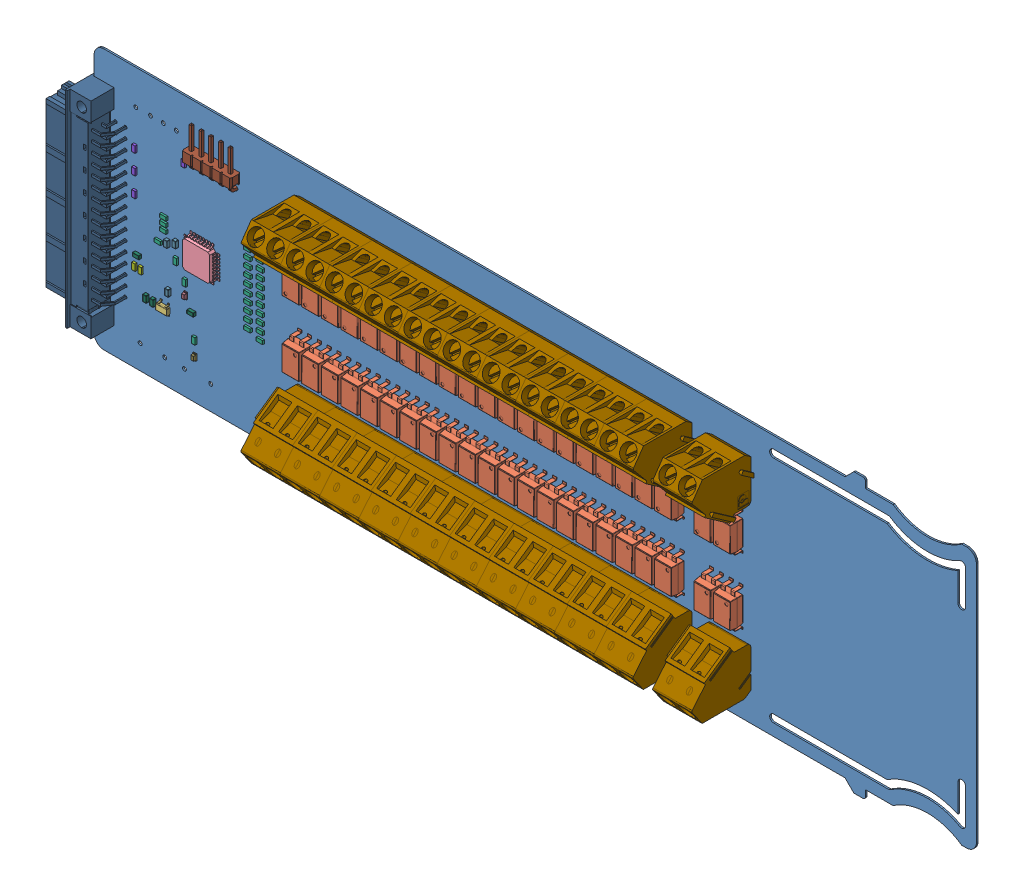
SolidWorks assembly DMM6500_Scan_card, configuration По умолчанию. Lengths in mm.
Overall size (235.68 72.14 18.8).
157 component instances, 15 part files, 0 mates.
Components (placement in the parent):
- DMM6500_Scan_card_BOARD-1: DMM6500_Scan_card_BOARD [По умолчанию] at origin size (228.6 72.14 0.41)
- SOP254P1000X380-4N_VOR1142B4-2-81: SOP254P1000X380-4N_VOR1142B4-2 [По умолчанию] at (125.83 50.8 0.4013) x (0 -1 0) z (0 0 1) size (10.02 4.7 3.8)
- SOP254P1000X380-4N_VOR1142B4-2-77: SOP254P1000X380-4N_VOR1142B4-2 [По умолчанию] at (120.75 50.8 0.4013) x (0 -1 0) z (0 0 1) size (10.02 4.7 3.8)
- SOP254P1000X380-4N_VOR1142B4-2-74: SOP254P1000X380-4N_VOR1142B4-2 [По умолчанию] at (115.67 50.8 0.4013) x (0 -1 0) z (0 0 1) size (10.02 4.7 3.8)
- SOP254P1000X380-4N_VOR1142B4-2-65: SOP254P1000X380-4N_VOR1142B4-2 [По умолчанию] at (110.59 50.8 0.4013) x (0 -1 0) z (0 0 1) size (10.02 4.7 3.8)
- SOP254P1000X380-4N_VOR1142B4-2-63: SOP254P1000X380-4N_VOR1142B4-2 [По умолчанию] at (105.51 50.8 0.4013) x (0 -1 0) z (0 0 1) size (10.02 4.7 3.8)
- SOP254P1000X380-4N_VOR1142B4-2-72: SOP254P1000X380-4N_VOR1142B4-2 [По умолчанию] at (100.43 50.8 0.4013) x (0 -1 0) z (0 0 1) size (10.02 4.7 3.8)
- SOP254P1000X380-4N_VOR1142B4-2-79: SOP254P1000X380-4N_VOR1142B4-2 [По умолчанию] at (95.35 50.8 0.4013) x (0 -1 0) z (0 0 1) size (10.02 4.7 3.8)
- SOP254P1000X380-4N_VOR1142B4-2-68: SOP254P1000X380-4N_VOR1142B4-2 [По умолчанию] at (90.27 50.8 0.4013) x (0 -1 0) z (0 0 1) size (10.02 4.7 3.8)
- SOP254P1000X380-4N_VOR1142B4-2-75: SOP254P1000X380-4N_VOR1142B4-2 [По умолчанию] at (85.19 50.8 0.4013) x (0 -1 0) z (0 0 1) size (10.02 4.7 3.8)
- SOP254P1000X380-4N_VOR1142B4-2-71: SOP254P1000X380-4N_VOR1142B4-2 [По умолчанию] at (80.11 50.8 0.4013) x (0 -1 0) z (0 0 1) size (10.02 4.7 3.8)
- SOP254P1000X380-4N_VOR1142B4-2-73: SOP254P1000X380-4N_VOR1142B4-2 [По умолчанию] at (176.63 50.8 0.4013) x (0 -1 0) z (0 0 1) size (10.02 4.7 3.8)
- SOP254P1000X380-4N_VOR1142B4-2-78: SOP254P1000X380-4N_VOR1142B4-2 [По умолчанию] at (171.55 50.8 0.4013) x (0 -1 0) z (0 0 1) size (10.02 4.7 3.8)
- SOP254P1000X380-4N_VOR1142B4-2-80: SOP254P1000X380-4N_VOR1142B4-2 [По умолчанию] at (166.47 50.8 0.4013) x (0 -1 0) z (0 0 1) size (10.02 4.7 3.8)
- SOP254P1000X380-4N_VOR1142B4-2-76: SOP254P1000X380-4N_VOR1142B4-2 [По умолчанию] at (161.39 50.8 0.4013) x (0 -1 0) z (0 0 1) size (10.02 4.7 3.8)
- SOP254P1000X380-4N_VOR1142B4-2-64: SOP254P1000X380-4N_VOR1142B4-2 [По умолчанию] at (156.31 50.8 0.4013) x (0 -1 0) z (0 0 1) size (10.02 4.7 3.8)
- SOP254P1000X380-4N_VOR1142B4-2-66: SOP254P1000X380-4N_VOR1142B4-2 [По умолчанию] at (151.23 50.8 0.4013) x (0 -1 0) z (0 0 1) size (10.02 4.7 3.8)
- SOP254P1000X380-4N_VOR1142B4-2-67: SOP254P1000X380-4N_VOR1142B4-2 [По умолчанию] at (146.15 50.8 0.4013) x (0 -1 0) z (0 0 1) size (10.02 4.7 3.8)
- SOP254P1000X380-4N_VOR1142B4-2-69: SOP254P1000X380-4N_VOR1142B4-2 [По умолчанию] at (141.07 50.8 0.4013) x (0 -1 0) z (0 0 1) size (10.02 4.7 3.8)
- SOP254P1000X380-4N_VOR1142B4-2-70: SOP254P1000X380-4N_VOR1142B4-2 [По умолчанию] at (135.99 50.8 0.4013) x (0 -1 0) z (0 0 1) size (10.02 4.7 3.8)
- SOP254P1000X380-4N_VOR1142B4-2-42: SOP254P1000X380-4N_VOR1142B4-2 [По умолчанию] at (130.91 50.8 0.4013) x (0 -1 0) z (0 0 1) size (10.02 4.7 3.8)
- SOP254P1000X380-4N_VOR1142B4-2-43: SOP254P1000X380-4N_VOR1142B4-2 [По умолчанию] at (191.87 50.8 0.4013) x (0 -1 0) z (0 0 1) size (10.02 4.7 3.8)
- SOP254P1000X380-4N_VOR1142B4-2-47: SOP254P1000X380-4N_VOR1142B4-2 [По умолчанию] at (186.79 50.8 0.4013) x (0 -1 0) z (0 0 1) size (10.02 4.7 3.8)
- SOP254P1000X380-4N_VOR1142B4-2-50: SOP254P1000X380-4N_VOR1142B4-2 [По умолчанию] at (125.83 67.91 0.4013) x (0 1 0) z (0 0 1) size (10.02 4.7 3.8)
- SOP254P1000X380-4N_VOR1142B4-2-48: SOP254P1000X380-4N_VOR1142B4-2 [По умолчанию] at (120.75 67.91 0.4013) x (0 1 0) z (0 0 1) size (10.02 4.7 3.8)
- SOP254P1000X380-4N_VOR1142B4-2-56: SOP254P1000X380-4N_VOR1142B4-2 [По умолчанию] at (115.67 67.91 0.4013) x (0 1 0) z (0 0 1) size (10.02 4.7 3.8)
- SOP254P1000X380-4N_VOR1142B4-2-44: SOP254P1000X380-4N_VOR1142B4-2 [По умолчанию] at (110.59 67.91 0.4013) x (0 1 0) z (0 0 1) size (10.02 4.7 3.8)
- SOP254P1000X380-4N_VOR1142B4-2-27: SOP254P1000X380-4N_VOR1142B4-2 [По умолчанию] at (105.51 67.91 0.4013) x (0 1 0) z (0 0 1) size (10.02 4.7 3.8)
- SOP254P1000X380-4N_VOR1142B4-2-58: SOP254P1000X380-4N_VOR1142B4-2 [По умолчанию] at (100.43 67.91 0.4013) x (0 1 0) z (0 0 1) size (10.02 4.7 3.8)
- SOP254P1000X380-4N_VOR1142B4-2-52: SOP254P1000X380-4N_VOR1142B4-2 [По умолчанию] at (95.35 67.91 0.4013) x (0 1 0) z (0 0 1) size (10.02 4.7 3.8)
- SOP254P1000X380-4N_VOR1142B4-2-59: SOP254P1000X380-4N_VOR1142B4-2 [По умолчанию] at (90.27 67.91 0.4013) x (0 1 0) z (0 0 1) size (10.02 4.7 3.8)
- SOP254P1000X380-4N_VOR1142B4-2-45: SOP254P1000X380-4N_VOR1142B4-2 [По умолчанию] at (85.19 67.91 0.4013) x (0 1 0) z (0 0 1) size (10.02 4.7 3.8)
- SOP254P1000X380-4N_VOR1142B4-2-46: SOP254P1000X380-4N_VOR1142B4-2 [По умолчанию] at (80.11 67.91 0.4013) x (0 1 0) z (0 0 1) size (10.02 4.7 3.8)
- SOP254P1000X380-4N_VOR1142B4-2-33: SOP254P1000X380-4N_VOR1142B4-2 [По умолчанию] at (176.63 67.91 0.4013) x (0 1 0) z (0 0 1) size (10.02 4.7 3.8)
- SOP254P1000X380-4N_VOR1142B4-2-60: SOP254P1000X380-4N_VOR1142B4-2 [По умолчанию] at (171.55 67.91 0.4013) x (0 1 0) z (0 0 1) size (10.02 4.7 3.8)
- SOP254P1000X380-4N_VOR1142B4-2-55: SOP254P1000X380-4N_VOR1142B4-2 [По умолчанию] at (166.47 67.91 0.4013) x (0 1 0) z (0 0 1) size (10.02 4.7 3.8)
- SOP254P1000X380-4N_VOR1142B4-2-57: SOP254P1000X380-4N_VOR1142B4-2 [По умолчанию] at (161.39 67.91 0.4013) x (0 1 0) z (0 0 1) size (10.02 4.7 3.8)
- SOP254P1000X380-4N_VOR1142B4-2-53: SOP254P1000X380-4N_VOR1142B4-2 [По умолчанию] at (156.31 67.91 0.4013) x (0 1 0) z (0 0 1) size (10.02 4.7 3.8)
- SOP254P1000X380-4N_VOR1142B4-2-41: SOP254P1000X380-4N_VOR1142B4-2 [По умолчанию] at (151.23 67.91 0.4013) x (0 1 0) z (0 0 1) size (10.02 4.7 3.8)
- SOP254P1000X380-4N_VOR1142B4-2-54: SOP254P1000X380-4N_VOR1142B4-2 [По умолчанию] at (146.15 67.91 0.4013) x (0 1 0) z (0 0 1) size (10.02 4.7 3.8)
- SOP254P1000X380-4N_VOR1142B4-2-40: SOP254P1000X380-4N_VOR1142B4-2 [По умолчанию] at (141.07 67.91 0.4013) x (0 1 0) z (0 0 1) size (10.02 4.7 3.8)
- SOP254P1000X380-4N_VOR1142B4-2-49: SOP254P1000X380-4N_VOR1142B4-2 [По умолчанию] at (135.99 67.91 0.4013) x (0 1 0) z (0 0 1) size (10.02 4.7 3.8)
- SOP254P1000X380-4N_VOR1142B4-2-61: SOP254P1000X380-4N_VOR1142B4-2 [По умолчанию] at (130.91 67.91 0.4013) x (0 1 0) z (0 0 1) size (10.02 4.7 3.8)
- SOP254P1000X380-4N_VOR1142B4-2-62: SOP254P1000X380-4N_VOR1142B4-2 [По умолчанию] at (191.87 67.91 0.4013) x (0 1 0) z (0 0 1) size (10.02 4.7 3.8)
- SOP254P1000X380-4N_VOR1142B4-2-51: SOP254P1000X380-4N_VOR1142B4-2 [По умолчанию] at (186.79 67.91 0.4013) x (0 1 0) z (0 0 1) size (10.02 4.7 3.8)
- SOT23-5-095_N_TPS73233DBVR-2-1: SOT23-5-095_N_TPS73233DBVR-2 [По умолчанию] at (43.9 43.2 0.4013) x (0 1 0) z (0 0 1) size (2.84 2.92 1.09)
- LQFP80P900X900X160-32N_STM32G070KBT6-2-1: LQFP80P900X900X160-32N_STM32G070KBT6-2 [По умолчанию] at (53.475 59.15 0.4013) size (9.2 9.2 1.55)
- RESC6431X06N_R2512X0.6mm_Generic-2-3: RESC6431X06N_R2512X0.6mm_Generic-2 [По умолчанию] at (124.56 43.48 0.0102) x (1 0 0) z (0 0 -1) size (6.45 3.25 0.65)
- RESC6431X06N_R2512X0.6mm_Generic-2-2: RESC6431X06N_R2512X0.6mm_Generic-2 [По умолчанию] at (114.4 43.48 0.0102) x (1 0 0) z (0 0 -1) size (6.45 3.25 0.65)
- RESC6431X06N_R2512X0.6mm_Generic-2-21: RESC6431X06N_R2512X0.6mm_Generic-2 [По умолчанию] at (104.24 43.48 0.0102) x (1 0 0) z (0 0 -1) size (6.45 3.25 0.65)
- RESC6431X06N_R2512X0.6mm_Generic-2-22: RESC6431X06N_R2512X0.6mm_Generic-2 [По умолчанию] at (94.08 43.48 0.0102) x (1 0 0) z (0 0 -1) size (6.45 3.25 0.65)
- RESC6431X06N_R2512X0.6mm_Generic-2-24: RESC6431X06N_R2512X0.6mm_Generic-2 [По умолчанию] at (83.92 43.48 0.0102) x (1 0 0) z (0 0 -1) size (6.45 3.25 0.65)
- RESC6431X06N_R2512X0.6mm_Generic-2-33: RESC6431X06N_R2512X0.6mm_Generic-2 [По умолчанию] at (175.36 43.48 0.0102) x (1 0 0) z (0 0 -1) size (6.45 3.25 0.65)
- RESC6431X06N_R2512X0.6mm_Generic-2-7: RESC6431X06N_R2512X0.6mm_Generic-2 [По умолчанию] at (165.2 43.48 0.0102) x (1 0 0) z (0 0 -1) size (6.45 3.25 0.65)
- RESC6431X06N_R2512X0.6mm_Generic-2-34: RESC6431X06N_R2512X0.6mm_Generic-2 [По умолчанию] at (155.04 43.48 0.0102) x (1 0 0) z (0 0 -1) size (6.45 3.25 0.65)
- RESC6431X06N_R2512X0.6mm_Generic-2-23: RESC6431X06N_R2512X0.6mm_Generic-2 [По умолчанию] at (144.88 43.48 0.0102) x (1 0 0) z (0 0 -1) size (6.45 3.25 0.65)
- RESC6431X06N_R2512X0.6mm_Generic-2-25: RESC6431X06N_R2512X0.6mm_Generic-2 [По умолчанию] at (134.72 43.48 0.0102) x (1 0 0) z (0 0 -1) size (6.45 3.25 0.65)
- RESC6431X06N_R2512X0.6mm_Generic-2-35: RESC6431X06N_R2512X0.6mm_Generic-2 [По умолчанию] at (124.56 75.23 0.0102) x (1 0 0) z (0 0 -1) size (6.45 3.25 0.65)
- RESC6431X06N_R2512X0.6mm_Generic-2-28: RESC6431X06N_R2512X0.6mm_Generic-2 [По умолчанию] at (114.4 75.23 0.0102) x (1 0 0) z (0 0 -1) size (6.45 3.25 0.65)
- RESC6431X06N_R2512X0.6mm_Generic-2-26: RESC6431X06N_R2512X0.6mm_Generic-2 [По умолчанию] at (104.24 75.23 0.0102) x (1 0 0) z (0 0 -1) size (6.45 3.25 0.65)
- RESC6431X06N_R2512X0.6mm_Generic-2-30: RESC6431X06N_R2512X0.6mm_Generic-2 [По умолчанию] at (94.08 75.23 0.0102) x (1 0 0) z (0 0 -1) size (6.45 3.25 0.65)
- RESC6431X06N_R2512X0.6mm_Generic-2-27: RESC6431X06N_R2512X0.6mm_Generic-2 [По умолчанию] at (83.92 75.23 0.0102) x (1 0 0) z (0 0 -1) size (6.45 3.25 0.65)
- RESC6431X06N_R2512X0.6mm_Generic-2-16: RESC6431X06N_R2512X0.6mm_Generic-2 [По умолчанию] at (175.36 75.23 0.0102) x (1 0 0) z (0 0 -1) size (6.45 3.25 0.65)
- RESC6431X06N_R2512X0.6mm_Generic-2-29: RESC6431X06N_R2512X0.6mm_Generic-2 [По умолчанию] at (165.2 75.23 0.0102) x (1 0 0) z (0 0 -1) size (6.45 3.25 0.65)
- RESC6431X06N_R2512X0.6mm_Generic-2-31: RESC6431X06N_R2512X0.6mm_Generic-2 [По умолчанию] at (155.04 75.23 0.0102) x (1 0 0) z (0 0 -1) size (6.45 3.25 0.65)
- RESC6431X06N_R2512X0.6mm_Generic-2-32: RESC6431X06N_R2512X0.6mm_Generic-2 [По умолчанию] at (144.88 75.23 0.0102) x (1 0 0) z (0 0 -1) size (6.45 3.25 0.65)
- RESC6431X06N_R2512X0.6mm_Generic-2-20: RESC6431X06N_R2512X0.6mm_Generic-2 [По умолчанию] at (134.72 75.23 0.0102) x (1 0 0) z (0 0 -1) size (6.45 3.25 0.65)
- RESC1608X06N_RC0603FR-07330RL-2-100: RESC1608X06N_RC0603FR-07330RL-2 [По умолчанию] at (51.7 39.9 0.4013) x (0 -1 0) z (0 0 1) size (1.7 0.9 0.55)
- RESC1608X06N_RC0603FR-07330RL-2-61: RESC1608X06N_RC0603FR-07330RL-2 [По умолчанию] at (42.4 57.4 0.4013) size (1.7 0.9 0.55)
- RESC1608X06N_RC0603FR-07330RL-2-54: RESC1608X06N_RC0603FR-07330RL-2 [По умолчанию] at (43.8 60.6 0.4013) size (1.7 0.9 0.55)
- RESC1608X06N_RC0603FR-07330RL-2-67: RESC1608X06N_RC0603FR-07330RL-2 [По умолчанию] at (43.8 62.1 0.4013) size (1.7 0.9 0.55)
- RESC1608X06N_RC0603FR-07330RL-2-59: RESC1608X06N_RC0603FR-07330RL-2 [По умолчанию] at (43.8 63.6 0.4013) size (1.7 0.9 0.55)
- RESC1608X06N_RC0603FR-07330RL-2-62: RESC1608X06N_RC0603FR-07330RL-2 [По умолчанию] at (49.3 51.7 0.4013) x (0 -1 0) z (0 0 1) size (1.7 0.9 0.55)
- RESC1608X06N_RC0603FR-07330RL-2-70: RESC1608X06N_RC0603FR-07330RL-2 [По умолчанию] at (46.9 55.3 0.4013) x (0 -1 0) z (0 0 1) size (1.7 0.9 0.55)
- RESC1608X06N_RC0603FR-07330RL-2-68: RESC1608X06N_RC0603FR-07330RL-2 [По умолчанию] at (68.85 58.4 0.0102) x (1 0 0) z (0 0 -1) size (1.7 0.9 0.55)
- RESC1608X06N_RC0603FR-07330RL-2-60: RESC1608X06N_RC0603FR-07330RL-2 [По умолчанию] at (68.825 58.4 0.4013) size (1.7 0.9 0.55)
- RESC1608X06N_RC0603FR-07330RL-2-52: RESC1608X06N_RC0603FR-07330RL-2 [По умолчанию] at (65.625 59.4 0.0102) x (1 0 0) z (0 0 -1) size (1.7 0.9 0.55)
- RESC1608X06N_RC0603FR-07330RL-2-69: RESC1608X06N_RC0603FR-07330RL-2 [По умолчанию] at (65.625 59.4 0.4013) size (1.7 0.9 0.55)
- RESC1608X06N_RC0603FR-07330RL-2-75: RESC1608X06N_RC0603FR-07330RL-2 [По умолчанию] at (68.825 48.4 0.0102) x (1 0 0) z (0 0 -1) size (1.7 0.9 0.55)
- RESC1608X06N_RC0603FR-07330RL-2-71: RESC1608X06N_RC0603FR-07330RL-2 [По умолчанию] at (68.825 48.4 0.4013) size (1.7 0.9 0.55)
- RESC1608X06N_RC0603FR-07330RL-2-73: RESC1608X06N_RC0603FR-07330RL-2 [По умолчанию] at (65.625 49.4 0.0102) x (1 0 0) z (0 0 -1) size (1.7 0.9 0.55)
- RESC1608X06N_RC0603FR-07330RL-2-72: RESC1608X06N_RC0603FR-07330RL-2 [По умолчанию] at (65.625 49.4 0.4013) size (1.7 0.9 0.55)
- RESC1608X06N_RC0603FR-07330RL-2-76: RESC1608X06N_RC0603FR-07330RL-2 [По умолчанию] at (68.825 50.4 0.0102) x (1 0 0) z (0 0 -1) size (1.7 0.9 0.55)
- RESC1608X06N_RC0603FR-07330RL-2-57: RESC1608X06N_RC0603FR-07330RL-2 [По умолчанию] at (68.825 50.4 0.4013) size (1.7 0.9 0.55)
- RESC1608X06N_RC0603FR-07330RL-2-55: RESC1608X06N_RC0603FR-07330RL-2 [По умолчанию] at (65.625 51.4 0.0102) x (1 0 0) z (0 0 -1) size (1.7 0.9 0.55)
- RESC1608X06N_RC0603FR-07330RL-2-56: RESC1608X06N_RC0603FR-07330RL-2 [По умолчанию] at (65.625 51.4 0.4013) size (1.7 0.9 0.55)
- RESC1608X06N_RC0603FR-07330RL-2-58: RESC1608X06N_RC0603FR-07330RL-2 [По умолчанию] at (68.825 52.4 0.0102) x (1 0 0) z (0 0 -1) size (1.7 0.9 0.55)
- RESC1608X06N_RC0603FR-07330RL-2-63: RESC1608X06N_RC0603FR-07330RL-2 [По умолчанию] at (68.825 52.4 0.4013) size (1.7 0.9 0.55)
- RESC1608X06N_RC0603FR-07330RL-2-64: RESC1608X06N_RC0603FR-07330RL-2 [По умолчанию] at (65.625 53.4 0.0102) x (1 0 0) z (0 0 -1) size (1.7 0.9 0.55)
- RESC1608X06N_RC0603FR-07330RL-2-65: RESC1608X06N_RC0603FR-07330RL-2 [По умолчанию] at (65.625 53.4 0.4013) size (1.7 0.9 0.55)
- RESC1608X06N_RC0603FR-07330RL-2-66: RESC1608X06N_RC0603FR-07330RL-2 [По умолчанию] at (68.825 54.4 0.0102) x (1 0 0) z (0 0 -1) size (1.7 0.9 0.55)
- RESC1608X06N_RC0603FR-07330RL-2-74: RESC1608X06N_RC0603FR-07330RL-2 [По умолчанию] at (68.825 54.4 0.4013) size (1.7 0.9 0.55)
- RESC1608X06N_RC0603FR-07330RL-2-53: RESC1608X06N_RC0603FR-07330RL-2 [По умолчанию] at (65.625 55.4 0.0102) x (1 0 0) z (0 0 -1) size (1.7 0.9 0.55)
- RESC1608X06N_RC0603FR-07330RL-2-85: RESC1608X06N_RC0603FR-07330RL-2 [По умолчанию] at (65.625 55.4 0.4013) size (1.7 0.9 0.55)
- RESC1608X06N_RC0603FR-07330RL-2-83: RESC1608X06N_RC0603FR-07330RL-2 [По умолчанию] at (68.825 56.4 0.0102) x (1 0 0) z (0 0 -1) size (1.7 0.9 0.55)
- RESC1608X06N_RC0603FR-07330RL-2-80: RESC1608X06N_RC0603FR-07330RL-2 [По умолчанию] at (68.825 56.4 0.4013) size (1.7 0.9 0.55)
- RESC1608X06N_RC0603FR-07330RL-2-91: RESC1608X06N_RC0603FR-07330RL-2 [По умолчанию] at (65.625 57.4 0.0102) x (1 0 0) z (0 0 -1) size (1.7 0.9 0.55)
- RESC1608X06N_RC0603FR-07330RL-2-90: RESC1608X06N_RC0603FR-07330RL-2 [По умолчанию] at (65.625 57.4 0.4013) size (1.7 0.9 0.55)
- RESC1608X06N_RC0603FR-07330RL-2-84: RESC1608X06N_RC0603FR-07330RL-2 [По умолчанию] at (65.625 69.4 0.0102) x (1 0 0) z (0 0 -1) size (1.7 0.9 0.55)
- RESC1608X06N_RC0603FR-07330RL-2-89: RESC1608X06N_RC0603FR-07330RL-2 [По умолчанию] at (65.625 69.4 0.4013) size (1.7 0.9 0.55)
- RESC1608X06N_RC0603FR-07330RL-2-92: RESC1608X06N_RC0603FR-07330RL-2 [По умолчанию] at (68.825 68.5 0.0102) x (1 0 0) z (0 0 -1) size (1.7 0.9 0.55)
- RESC1608X06N_RC0603FR-07330RL-2-93: RESC1608X06N_RC0603FR-07330RL-2 [По умолчанию] at (68.85 68.5 0.4013) size (1.7 0.9 0.55)
- RESC1608X06N_RC0603FR-07330RL-2-99: RESC1608X06N_RC0603FR-07330RL-2 [По умолчанию] at (65.625 67.4 0.0102) x (1 0 0) z (0 0 -1) size (1.7 0.9 0.55)
- RESC1608X06N_RC0603FR-07330RL-2-81: RESC1608X06N_RC0603FR-07330RL-2 [По умолчанию] at (65.625 67.4 0.4013) size (1.7 0.9 0.55)
- RESC1608X06N_RC0603FR-07330RL-2-86: RESC1608X06N_RC0603FR-07330RL-2 [По умолчанию] at (68.825 66.4 0.0102) x (1 0 0) z (0 0 -1) size (1.7 0.9 0.55)
- RESC1608X06N_RC0603FR-07330RL-2-77: RESC1608X06N_RC0603FR-07330RL-2 [По умолчанию] at (68.825 66.4 0.4013) size (1.7 0.9 0.55)
- RESC1608X06N_RC0603FR-07330RL-2-88: RESC1608X06N_RC0603FR-07330RL-2 [По умолчанию] at (65.625 65.4 0.0102) x (1 0 0) z (0 0 -1) size (1.7 0.9 0.55)
- RESC1608X06N_RC0603FR-07330RL-2-87: RESC1608X06N_RC0603FR-07330RL-2 [По умолчанию] at (65.625 65.4 0.4013) size (1.7 0.9 0.55)
- RESC1608X06N_RC0603FR-07330RL-2-78: RESC1608X06N_RC0603FR-07330RL-2 [По умолчанию] at (68.825 64.4 0.0102) x (1 0 0) z (0 0 -1) size (1.7 0.9 0.55)
- RESC1608X06N_RC0603FR-07330RL-2-94: RESC1608X06N_RC0603FR-07330RL-2 [По умолчанию] at (68.825 64.4 0.4013) size (1.7 0.9 0.55)
- RESC1608X06N_RC0603FR-07330RL-2-95: RESC1608X06N_RC0603FR-07330RL-2 [По умолчанию] at (65.625 63.4 0.0102) x (1 0 0) z (0 0 -1) size (1.7 0.9 0.55)
- RESC1608X06N_RC0603FR-07330RL-2-96: RESC1608X06N_RC0603FR-07330RL-2 [По умолчанию] at (65.625 63.4 0.4013) size (1.7 0.9 0.55)
- RESC1608X06N_RC0603FR-07330RL-2-97: RESC1608X06N_RC0603FR-07330RL-2 [По умолчанию] at (68.825 62.4 0.0102) x (1 0 0) z (0 0 -1) size (1.7 0.9 0.55)
- RESC1608X06N_RC0603FR-07330RL-2-98: RESC1608X06N_RC0603FR-07330RL-2 [По умолчанию] at (68.825 62.4 0.4013) size (1.7 0.9 0.55)
- RESC1608X06N_RC0603FR-07330RL-2-79: RESC1608X06N_RC0603FR-07330RL-2 [По умолчанию] at (65.625 61.4 0.0102) x (1 0 0) z (0 0 -1) size (1.7 0.9 0.55)
- RESC1608X06N_RC0603FR-07330RL-2-82: RESC1608X06N_RC0603FR-07330RL-2 [По умолчанию] at (65.625 61.4 0.4013) size (1.7 0.9 0.55)
- RESC1608X06N_RC0603FR-07330RL-2-50: RESC1608X06N_RC0603FR-07330RL-2 [По умолчанию] at (68.825 60.4 0.0102) x (1 0 0) z (0 0 -1) size (1.7 0.9 0.55)
- RESC1608X06N_RC0603FR-07330RL-2-51: RESC1608X06N_RC0603FR-07330RL-2 [По умолчанию] at (68.825 60.4 0.4013) size (1.7 0.9 0.55)
- RESC1608X06N_RC0603FR-070RL-2-1: RESC1608X06N_RC0603FR-070RL-2 [По умолчанию] at (36.2 48.7 0.4013) x (0 -1 0) z (0 0 1) size (1.7 0.9 0.55)
- RESC1608X06N_RC0603FR-070RL-2-2: RESC1608X06N_RC0603FR-070RL-2 [По умолчанию] at (37.8 48.7 0.4013) x (0 1 0) z (0 0 1) size (1.7 0.9 0.55)
- RESC1608X06N_RC0603FR-0710KL-2-3: RESC1608X06N_RC0603FR-0710KL-2 [По умолчанию] at (36.2 65 0.4013) x (0 1 0) z (0 0 1) size (1.7 0.9 0.55)
- RESC1608X06N_RC0603FR-0710KL-2-2: RESC1608X06N_RC0603FR-0710KL-2 [По умолчанию] at (36.2 70.125 0.4013) x (0 1 0) z (0 0 1) size (1.7 0.9 0.55)
- RESC1608X06N_RC0603FR-0710KL-2-4: RESC1608X06N_RC0603FR-0710KL-2 [По умолчанию] at (36.2 75.2 0.4013) x (0 1 0) z (0 0 1) size (1.7 0.9 0.55)
- RESC1608X06N_RC0603FR-0710KL-2-5: RESC1608X06N_RC0603FR-0710KL-2 [По умолчанию] at (49 78.3 0.4013) x (0 1 0) z (0 0 1) size (1.7 0.9 0.55)
- Phoenix_Contact_1733570_1733570-2-3: Phoenix_Contact_1733570_1733570-2 [По умолчанию] at (124.56 38.4 0.4013) x (-1 0 0) z (0 0 1) size (10.9 13.4 18.8)
- Phoenix_Contact_1733570_1733570-2-2: Phoenix_Contact_1733570_1733570-2 [По умолчанию] at (114.4 38.4 0.4013) x (-1 0 0) z (0 0 1) size (10.9 13.4 18.8)
- Phoenix_Contact_1733570_1733570-2-24: Phoenix_Contact_1733570_1733570-2 [По умолчанию] at (104.24 38.4 0.4013) x (-1 0 0) z (0 0 1) size (10.9 13.4 18.8)
- Phoenix_Contact_1733570_1733570-2-32: Phoenix_Contact_1733570_1733570-2 [По умолчанию] at (94.08 38.4 0.4013) x (-1 0 0) z (0 0 1) size (10.9 13.4 18.8)
- Phoenix_Contact_1733570_1733570-2-25: Phoenix_Contact_1733570_1733570-2 [По умолчанию] at (83.92 38.4 0.4013) x (-1 0 0) z (0 0 1) size (10.9 13.4 18.8)
- Phoenix_Contact_1733570_1733570-2-35: Phoenix_Contact_1733570_1733570-2 [По умолчанию] at (175.36 38.4 0.4013) x (-1 0 0) z (0 0 1) size (10.9 13.4 18.8)
- Phoenix_Contact_1733570_1733570-2-26: Phoenix_Contact_1733570_1733570-2 [По умолчанию] at (165.2 38.4 0.4013) x (-1 0 0) z (0 0 1) size (10.9 13.4 18.8)
- Phoenix_Contact_1733570_1733570-2-23: Phoenix_Contact_1733570_1733570-2 [По умолчанию] at (155.04 38.4 0.4013) x (-1 0 0) z (0 0 1) size (10.9 13.4 18.8)
- Phoenix_Contact_1733570_1733570-2-33: Phoenix_Contact_1733570_1733570-2 [По умолчанию] at (144.88 38.4 0.4013) x (-1 0 0) z (0 0 1) size (10.9 13.4 18.8)
- Phoenix_Contact_1733570_1733570-2-10: Phoenix_Contact_1733570_1733570-2 [По умолчанию] at (134.72 38.4 0.4013) x (-1 0 0) z (0 0 1) size (10.9 13.4 18.8)
- Phoenix_Contact_1733570_1733570-2-28: Phoenix_Contact_1733570_1733570-2 [По умолчанию] at (190.6 38.4 0.4013) x (-1 0 0) z (0 0 1) size (10.9 13.4 18.8)
- Phoenix_Contact_1733570_1733570-2-27: Phoenix_Contact_1733570_1733570-2 [По умолчанию] at (124.56 80.31 0.4013) size (10.9 13.4 18.8)
- Phoenix_Contact_1733570_1733570-2-21: Phoenix_Contact_1733570_1733570-2 [По умолчанию] at (114.4 80.31 0.4013) size (10.9 13.4 18.8)
- Phoenix_Contact_1733570_1733570-2-29: Phoenix_Contact_1733570_1733570-2 [По умолчанию] at (104.24 80.31 0.4013) size (10.9 13.4 18.8)
- Phoenix_Contact_1733570_1733570-2-30: Phoenix_Contact_1733570_1733570-2 [По умолчанию] at (94.08 80.31 0.4013) size (10.9 13.4 18.8)
- Phoenix_Contact_1733570_1733570-2-22: Phoenix_Contact_1733570_1733570-2 [По умолчанию] at (83.92 80.31 0.4013) size (10.9 13.4 18.8)
- Phoenix_Contact_1733570_1733570-2-31: Phoenix_Contact_1733570_1733570-2 [По умолчанию] at (175.36 80.31 0.4013) size (10.9 13.4 18.8)
- Phoenix_Contact_1733570_1733570-2-34: Phoenix_Contact_1733570_1733570-2 [По умолчанию] at (165.2 80.31 0.4013) size (10.9 13.4 18.8)
- Phoenix_Contact_1733570_1733570-2-36: Phoenix_Contact_1733570_1733570-2 [По умолчанию] at (155.04 80.31 0.4013) size (10.9 13.4 18.8)
- Phoenix_Contact_1733570_1733570-2-20: Phoenix_Contact_1733570_1733570-2 [По умолчанию] at (144.88 80.31 0.4013) size (10.9 13.4 18.8)
- Phoenix_Contact_1733570_1733570-2-38: Phoenix_Contact_1733570_1733570-2 [По умолчанию] at (134.72 80.31 0.4013) size (10.9 13.4 18.8)
- Phoenix_Contact_1733570_1733570-2-37: Phoenix_Contact_1733570_1733570-2 [По умолчанию] at (190.6 80.31 0.4013) size (10.9 13.4 18.8)
- Molex_85050-0000_85050-0000-2-1: Molex_85050-0000_85050-0000-2 [По умолчанию] at (31.015 59.425 0.4013) x (0 1 0) z (0 0 1) size (53.36 15.33 9.55)
- WE_61300511021_61300511021-2-1: WE_61300511021_61300511021-2 [По умолчанию] at (57.1 81.87 0.4013) x (-1 0 0) z (0 0 1) size (12.7 10.36 5.54)
- LED0603red_LED0603red-2-1: LED0603red_LED0603red-2 [По умолчанию] at (51.7 36.1 0.4013) x (0 -1 0) z (0 0 1) size (1.6 0.8 0.85)
- LED0603green_LED0603green-2-1: LED0603green_LED0603green-2 [По умолчанию] at (49.3 48.7 0.4013) x (0 -1 0) z (0 0 1) size (1.6 0.8 0.85)
- CAPC1608X08N_CC0603KRX7R9BB104-2-1: CAPC1608X08N_CC0603KRX7R9BB104-2 [По умолчанию] at (45 47.4 0.4013) x (0 -1 0) z (0 0 1) size (1.7 0.9 0.8)
- CAPC1608X08N_CC0603KRX7R9BB104-2-4: CAPC1608X08N_CC0603KRX7R9BB104-2 [По умолчанию] at (44.7 58.2 0.4013) x (0 -1 0) z (0 0 1) size (1.7 0.9 0.8)
- CAPC1608X08N_CC0603KRX7R9BB104-2-3: CAPC1608X08N_CC0603KRX7R9BB104-2 [По умолчанию] at (46.9 59.2 0.4013) x (0 -1 0) z (0 0 1) size (1.7 0.9 0.8)
- CAPC1608X08N_CC0603KRX7R7BB105-2-7: CAPC1608X08N_CC0603KRX7R7BB105-2 [По умолчанию] at (51.1 45.8 0.4013) x (-1 0 0) z (0 0 1) size (1.7 0.9 0.8)
- CAPC1608X08N_CC0603KRX7R7BB105-2-5: CAPC1608X08N_CC0603KRX7R7BB105-2 [По умолчанию] at (41.1 43.2 0.4013) x (0 1 0) z (0 0 1) size (1.7 0.9 0.8)
- CAPC1608X08N_CC0603KRX7R7BB105-2-6: CAPC1608X08N_CC0603KRX7R7BB105-2 [По умолчанию] at (37 51.6 0.4013) x (-1 0 0) z (0 0 1) size (1.7 0.9 0.8)
- CAPC1608X08N_CC0603KRX7R7BB105-2-4: CAPC1608X08N_CC0603KRX7R7BB105-2 [По умолчанию] at (39.3 43.2 0.4013) x (0 -1 0) z (0 0 1) size (1.7 0.9 0.8)
